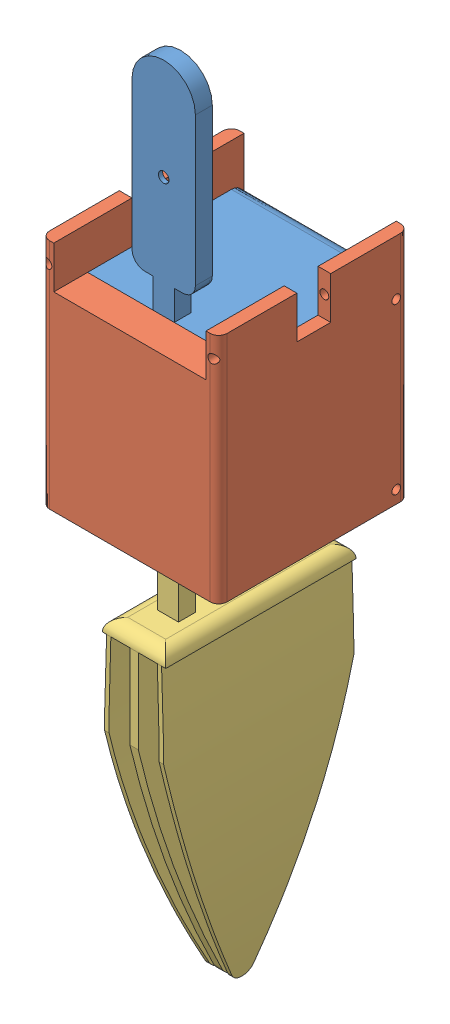
SolidWorks assembly test2, configuration 預設. Lengths in mm.
Overall size (42 211.39 52.29).
3 component instances, 3 part files, 5 mates.
Components (placement in the parent):
- little_connect2-1: little_connect2 [預設] at (-13.2814 -5.9422 112) size (36 97.5 37)
- little_connect_part2_3_final-1: little_connect_part2_3_final [預設] at (-18.7359 -24.0331 119) x (1 0 0) z (0 0 -1) size (42 55 50.58)
- littletail3-1: littletail3 [預設] at (-12.2814 -64.8236 114) size (19.72 152.51 46.77)
Mates (geometry in assembly coordinates):
- 重合/共線/共點1: coincident: plane of little_connect2-1 through (-13.2814 49.0578 116) normal (0 0 1); plane of littletail3-1 through (-12.2814 -9.8236 116) normal (0 0 1)
- 重合/共線/共點2: coincident: plane of little_connect2-1 through (-19.7814 -10.9422 81) normal (1 0 0); plane of littletail3-1 through (-19.7814 -56.8236 112) normal (-1 0 0)
- 同軸心1: concentric: cylinder of little_connect2-1 through (-26.2814 1.0578 82) axis (-1 0 0) radius 1.025; cylinder of little_connect_part2_3_final-1 through (11.2186 1.0578 82) axis (-1 0 0) radius 1.025
- 同軸心2: concentric: cylinder of little_connect2-1 through (-26.2814 -37.9422 82) axis (-1 0 0) radius 1.025; cylinder of little_connect_part2_3_final-1 through (11.2186 -37.9422 82) axis (-1 0 0) radius 1.025
- 重合/共線/共點3: coincident: plane of little_connect2-1 through (-31.2814 4.0578 79) normal (-1 0 0); plane of little_connect_part2_3_final-1 through (-31.2814 9.0578 116) normal (1 0 0)
